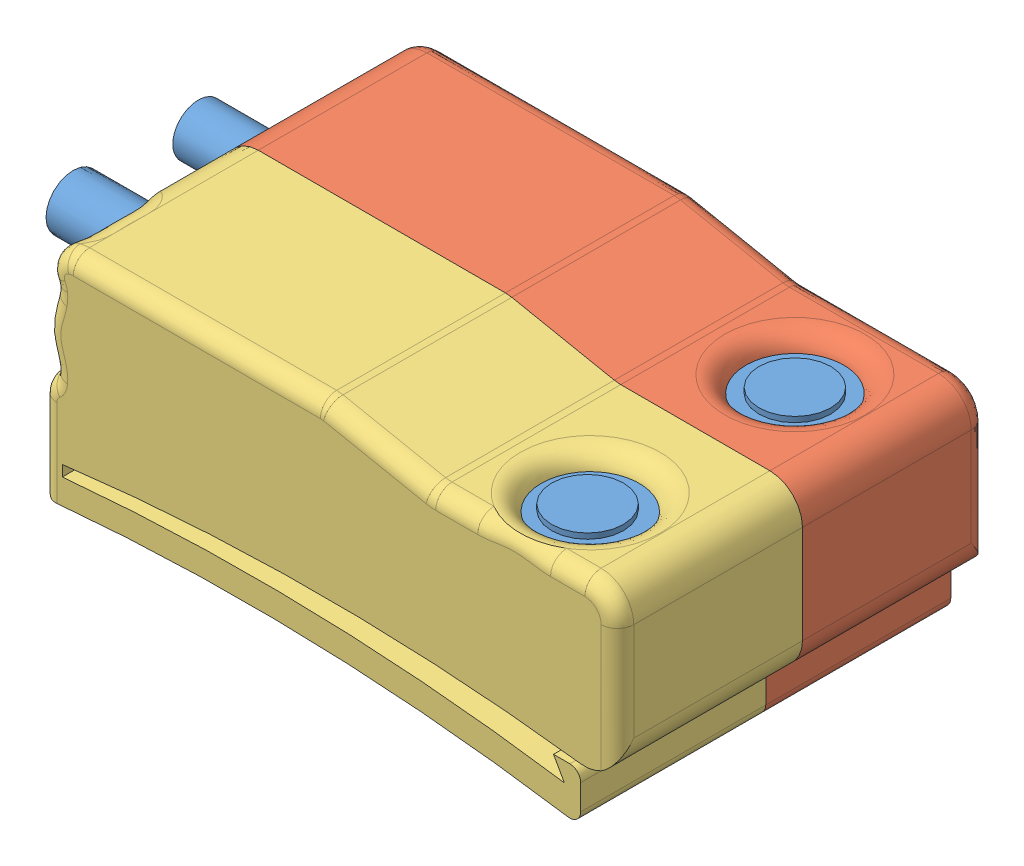
SolidWorks assembly PTT, configuration Standard. Lengths in mm.
Overall size (62 21.83 34.06).
3 component instances, 3 part files, 6 mates.
Components (placement in the parent):
- PTT-1: PTT [Standard] at (-33.1783 1.4396 60) size (60 11.5 31)
- Housing-Right-1: Housing-Right [Standard] at (17.3217 -4.0604 27) size (53 21.83 19)
- Housing-Left-3: Housing-Left [Standard] at (17.3217 -4.0604 59) size (53.18 21.83 17.06)
Mates (geometry in assembly coordinates):
- Deckungsgleich1: coincident anti-aligned: plane of PTT-1 through (-33.1783 2.9396 29) normal (0 0 -1); plane of Housing-Right-1 through (-34.6783 -6.4572 29) normal (0 0 1)
- Deckungsgleich2: coincident anti-aligned: plane of PTT-1 through (15.3217 2.9396 60) normal (1 0 0); plane of Housing-Right-1 through (15.3217 -1.5604 44) normal (-1 0 0)
- Deckungsgleich3: coincident anti-aligned: plane of PTT-1 through (-33.1783 -1.5604 60) normal (0 -1 0); plane of Housing-Right-1 through (-33.6783 -1.5604 44) normal (0 1 0)
- Deckungsgleich4: coincident aligned: plane of Housing-Right-1 through (-35.6783 9.9396 29) normal (-1 0 0); plane of Housing-Left-3 through (-35.6783 9.9396 61) normal (-1 0 0)
- Deckungsgleich5: coincident aligned: plane of Housing-Right-1 through (-9.9754 12.9396 29) normal (0 1 0); plane of Housing-Left-3 through (-9.9754 12.9396 61) normal (0 1 0)
- Deckungsgleich7: coincident anti-aligned: plane of Housing-Right-1 through (-32.6783 9.9396 44) normal (0 0 1); plane of Housing-Left-3 through (-32.6783 9.9396 44) normal (0 0 -1)
